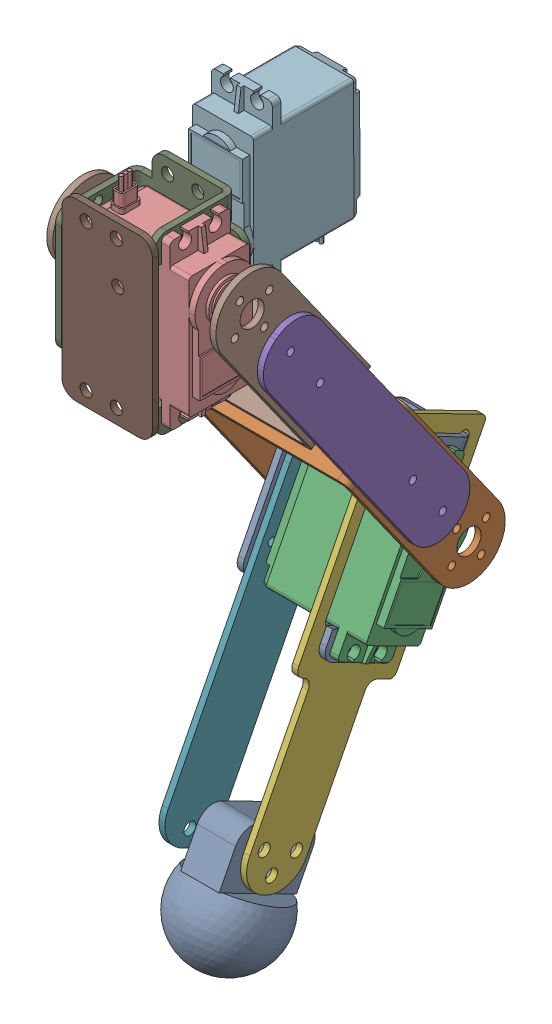
SolidWorks assembly MirrorMirrorleg, configuration Default. Lengths in mm.
Overall size (60 255.94 116.66).
13 component instances, 8 part files, 0 mates.
Components (placement in the parent):
- MirrorMirrorMulti Purpose Bracket-1: MirrorMirrorMulti Purpose Bracket [Défaut] at (0.2403 42.0249 -104.6986) x (0 0.890806 -0.454383) z (1 0 0) size (58 27 37.5)
- MirrorMirrorU Long Bracket-1: MirrorMirrorU Long Bracket [Défaut] at (25.2403 101.7982 -65.7711) x (-1 0 0) z (0 -0.578856 0.81543) size (56 65 24)
- Parça2 - Kopya-1: Parça2 - Kopya [Varsayılan] at (41.8386 78.3933 -95.2747) x (0 0.890806 -0.454383) z (0 -0.454383 -0.890806) size (56.95 39.84 20.1)
- MirrorMirrorleg_upper_1-1: MirrorMirrorleg_upper_1 [Default] at (-2.7597 109.137 -60.5614) x (0 0.81543 0.578856) z (0 -0.578856 0.81543) size (102 2 21.12)
- MirrorMirrorleg_upper_1-2: MirrorMirrorleg_upper_1 [Default] at (55.2403 109.137 -60.5614) x (0 -0.81543 -0.578856) z (0 0.578856 -0.81543) size (102 2 21.12)
- MirrorMirrorleg_lower_1-1: MirrorMirrorleg_lower_1 [Default] at (29.2403 3.3504 -68.2787) x (0 0.890806 -0.454383) z (0 -0.454383 -0.890806) size (123.5 2 37)
- MirrorMirrorleg_lower_2-1: MirrorMirrorleg_lower_2 [Default] at (2.2403 3.3504 -68.2787) x (0 0.890806 -0.454383) z (0 -0.454383 -0.890806) size (108.5 2 21.12)
- MirrorMirrorU Long Bracket-2: MirrorMirrorU Long Bracket [Défaut] at (25.2403 116.4759 -55.3517) x (1 0 0) z (0 -0.578856 0.81543) size (56 65 24)
- MirrorMirrorMulti Purpose Bracket-2: MirrorMirrorMulti Purpose Bracket [Défaut] at (0.2403 148.6937 -39.5423) x (0 1 0) z (1 0 0) size (58 27 37.5)
- Parça2 - Kopya-2: Parça2 - Kopya [Varsayılan] at (41.8386 178.1786 -14.6224) x (0 1 0) z (0 0 -1) size (56.95 39.84 20.1)
- MirrorMirrorhip_1-1: MirrorMirrorhip_1 [Default] at (19.3703 148.6937 -12.5423) size (30 58 2)
- Parça2 - Kopya-3: Parça2 - Kopya [Varsayılan] at (32.9621 140.9816 -45.944) x (0.002264 -0.999997 0) z (-0.999997 -0.002264 0) size (56.95 39.84 20.1)
- MirrorMirrorfoot-1: MirrorMirrorfoot [Default] at (22.8703 -37.6267 -47.3771) x (0 0.454383 0.890806) z (-1 0 0) size (32 41 32)
